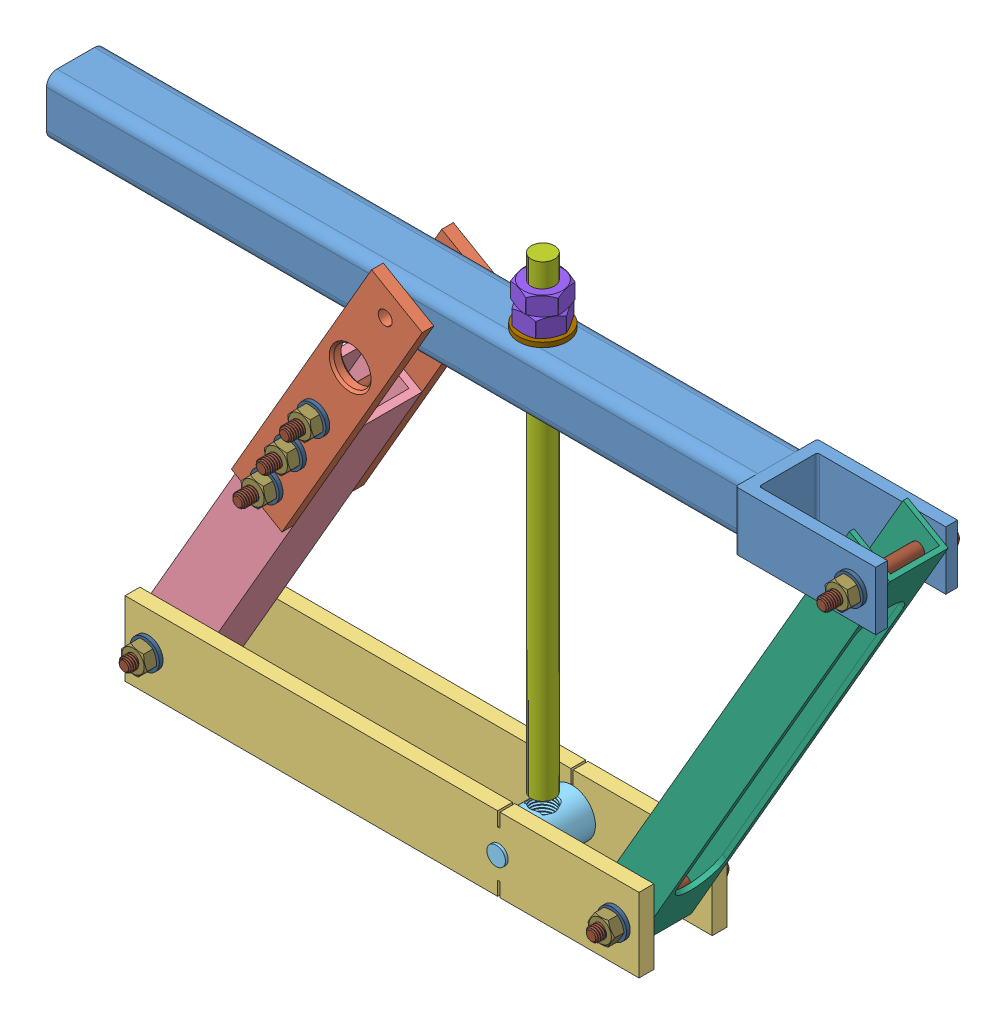
SolidWorks assembly ASSEMBLY, configuration Default. Lengths in mm.
Overall size (361.06 229.58 55.41).
36 component instances, 12 part files, 78 mates.
Components (placement in the parent):
- Base-1: Base [Default<As Machined>] at (-498.0765 -12.5 12.5) x (0 0 1) z (0 1 0) size (35 360 25)
- Base Arm-1: Base Arm [Default] at (-392.2512 -114.0128 0) x (-0.866025 0.5 0) z (0 0 -1) size (25 120 5)
- Beam-1: Beam [Default] at (-238.0765 -201.5801 0) x (-1 0 0) z (0 0 -1) size (220 31.75 6.35)
- Link-1: Link [Default] at (-362.2512 -62.0513 25) x (-0.866025 0.5 0) z (-0.5 -0.866025 0) size (25 25 160)
- nut-1: nut [Default] at (-313.4989 -170.565 32.5) x (0 0 -1) z (0 -1 0) size (40 20 25.35)
- strut-1: strut [Default] at (-290.91 81.512 250.1369) x (-0.866025 0.5 0) z (-0.5 -0.866025 0) size (20 25 220)
- tie-1: tie [Default] at (-298.0765 -172 12.5) x (-0.966291 0 0.257452) z (-0.257452 0 -0.966291) size (10 200 10)
- Beam-2: Beam [Default] at (-238.0765 -201.5801 31.35) x (-1 0 0) z (0 0 -1) size (220 31.75 6.35)
- Base Arm-2: Base Arm [Default] at (-392.2512 -114.0128 30) x (-0.866025 0.5 0) z (0 0 -1) size (25 120 5)
- M10-2: M10 [Default] at (-298.0765 6 12.5) x (-0.036581 0 -0.999331) z (0 -1 0) size (17 19.57 9.05)
- M10-3: M10 [Default] at (-298.0765 14 12.5) x (0.288728 0 -0.957411) z (0 -1 0) size (17 19.57 9.05)
- washer 10mm-1: washer 10mm [Default] at (-298.0765 2 12.5) x (-0.841207 0 -0.540714) z (0 -1 0) size (20.7 20.7 2)
- washer 6mm-1: washer 6mm [Default] at (-248.0765 -185.7051 32.95) x (-0.249725 -0.968317 0) z (0 0 -1) size (12.5 12.5 1.6)
- washer 6mm-2: washer 6mm [Default] at (-148.0765 -12.5 31.6) x (-0.286838 -0.957979 0) z (0 0 -1) size (12.5 12.5 1.6)
- washer 6mm-3: washer 6mm [Default] at (-448.0765 -185.7051 32.95) x (-0.286838 -0.957979 0) z (0 0 -1) size (12.5 12.5 1.6)
- washer 6mm-4: washer 6mm [Default] at (-388.0765 -81.782 31.6) x (-0.280456 -0.959867 0) z (0 0 -1) size (12.5 12.5 1.6)
- washer 6mm-5: washer 6mm [Default] at (-398.0765 -99.1025 31.6) x (-0.33668 -0.941619 0) z (0 0 -1) size (12.5 12.5 1.6)
- washer 6mm-6: washer 6mm [Default] at (-378.0765 -64.4615 31.6) x (-0.286026 -0.958222 0) z (0 0 -1) size (12.5 12.5 1.6)
- washer 6mm-7: washer 6mm [Default] at (-398.0765 -99.1025 -5) x (0.991493 -0.130162 0) z (0 0 -1) size (12.5 12.5 1.6)
- washer 6mm-8: washer 6mm [Default] at (-248.0765 -185.7051 -6.35) x (-0.263868 -0.964559 0) z (0 0 -1) size (12.5 12.5 1.6)
- washer 6mm-9: washer 6mm [Default] at (-448.0765 -185.7051 -6.35) x (-0.233498 -0.972357 0) z (0 0 -1) size (12.5 12.5 1.6)
- washer 6mm-10: washer 6mm [Default] at (-388.0765 -81.782 -5) x (-0.289092 -0.957301 0) z (0 0 -1) size (12.5 12.5 1.6)
- washer 6mm-11: washer 6mm [Default] at (-148.0765 -12.5 -5) x (-0.286838 -0.957979 0) z (0 0 -1) size (12.5 12.5 1.6)
- washer 6mm-12: washer 6mm [Default] at (-378.0765 -64.4615 -5) x (-0.274028 -0.961722 0) z (0 0 -1) size (12.5 12.5 1.6)
- m6 bolt-1: m6 bolt [Default] at (-148.0765 -12.5 -6.8) x (0.287505 0.957779 0) z (0 0 1) size (11.55 10 54.06)
- m6 nut-1: m6 nut [Default] at (-448.0765 -185.7051 32.95) x (0.693542 0.720416 0) z (0 0 1) size (11.55 10 5.69)
- m6 bolt-2: m6 bolt [Default] at (-378.0765 -64.4615 -6.8) x (0.287505 0.957779 0) z (0 0 1) size (11.55 10 54.06)
- m6 bolt-3: m6 bolt [Default] at (-398.0765 -99.1025 -6.8) x (0.287505 0.957779 0) z (0 0 1) size (11.55 10 54.06)
- m6 bolt-4: m6 bolt [Default] at (-388.0765 -81.782 -6.8) x (0.287505 0.957779 0) z (0 0 1) size (11.55 10 54.06)
- m6 bolt-5: m6 bolt [Default] at (-448.0765 -185.7051 -8.15) x (0.287505 0.957779 0) z (0 0 1) size (11.55 10 54.06)
- m6 bolt-6: m6 bolt [Default] at (-248.0765 -185.7051 -8.15) x (0.287505 0.957779 0) z (0 0 1) size (11.55 10 54.06)
- m6 nut-2: m6 nut [Default] at (-248.0765 -185.7051 32.95) x (-0.486561 0.873647 0) z (0 0 1) size (11.55 10 5.69)
- m6 nut-4: m6 nut [Default] at (-388.0765 -81.782 31.6) x (0.693542 0.720416 0) z (0 0 1) size (11.55 10 5.69)
- m6 nut-5: m6 nut [Default] at (-378.0765 -64.4615 31.6) x (0.693542 0.720416 0) z (0 0 1) size (11.55 10 5.69)
- m6 nut-6: m6 nut [Default] at (-398.0765 -99.1025 31.6) x (0.693542 0.720416 0) z (0 0 1) size (11.55 10 5.69)
- m6 nut-7: m6 nut [Default] at (-148.0765 -12.5 31.6) x (0.693542 0.720416 0) z (0 0 1) size (11.55 10 5.69)
Mates (geometry in assembly coordinates):
- Coincident1: coincident anti-aligned: plane of Base-1 through (-193.0765 0 25) normal (0 0 -1); plane of strut-1 through (-247.0143 -197.8653 25) normal (0 0 1)
- Concentric1: concentric aligned: circle of Base-1; circle of strut-1
- Coincident3: coincident anti-aligned: plane of Beam-1 through (-238.0765 -201.5801 0) normal (0 0 1); plane of strut-1 through (-247.0143 -197.8653 0) normal (0 0 -1)
- Concentric2: concentric aligned: circle of Beam-1; circle of strut-1
- Coincident5: coincident anti-aligned: plane of strut-1 through (-247.0143 -197.8653 25) normal (0 0 1); plane of Beam-2 through (-238.0765 -201.5801 25) normal (0 0 -1)
- Concentric3: concentric anti-aligned: cylinder of strut-1 through (-248.0765 -185.7051 220) axis (0 0 -1) radius 3; cylinder of Beam-2 through (-248.0765 -185.7051 25) axis (0 0 1) radius 3
- Concentric4: concentric aligned: cylinder of nut-1 through (-298.0765 -185.7051 25) axis (0 0 1) radius 4; cylinder of Beam-2 through (-298.0765 -185.7051 25) axis (0 0 1) radius 4
- Concentric5: concentric anti-aligned: cylinder of Beam-1 through (-298.0765 -185.7051 -6.35) axis (0 0 1) radius 4; cylinder of nut-1 through (-298.0765 -185.7051 0) axis (0 0 -1) radius 4
- Coincident6: coincident anti-aligned: plane of Beam-1 through (-238.0765 -201.5801 0) normal (0 0 1); plane of nut-1 through (-298.0765 -185.7051 0) normal (0 0 -1)
- Coincident7: coincident anti-aligned: plane of Beam-1 through (-238.0765 -201.5801 0) normal (0 0 1); plane of Link-1 through (-442.2512 -200.6153 0) normal (0 0 -1)
- Coincident8: coincident aligned: cylinder of Beam-1 through (-448.0765 -185.7051 -6.35) axis (0 0 1) radius 3; circle of Link-1
- Concentric6: concentric aligned: cylinder of Base Arm-1 through (-398.0765 -99.1025 -5) axis (0 0 1) radius 3; cylinder of Link-1 through (-398.0765 -99.1025 0) axis (0 0 1) radius 3
- Coincident9: coincident aligned: cylinder of Base Arm-1 through (-378.0765 -64.4615 -5) axis (0 0 1) radius 3; circle of Link-1
- Coincident10: coincident anti-aligned: plane of Base Arm-1 through (-392.2512 -114.0128 0) normal (0 0 1); plane of Link-1 through (-442.2512 -200.6153 0) normal (0 0 -1)
- Concentric7: concentric aligned: cylinder of Link-1 through (-378.0765 -64.4615 0) axis (0 0 1) radius 3; cylinder of Base Arm-2 through (-378.0765 -64.4615 25) axis (0 0 1) radius 3
- Coincident11: coincident anti-aligned: plane of Link-1 through (-442.2512 -200.6153 25) normal (0 0 1); plane of Base Arm-2 through (-392.2512 -114.0128 25) normal (0 0 -1)
- Concentric8: concentric anti-aligned: cylinder of Base-1 through (-298.0765 -3 12.5) axis (0 1 0) radius 5.25; cylinder of tie-1 through (-298.0765 28 12.5) axis (0 -1 0) radius 5
- Coincident13: coincident anti-aligned: cylinder of Link-1 through (-398.0765 -99.1025 0) axis (0 0 1) radius 3; circle of Base Arm-2
- Coincident14: coincident aligned: circle of nut-1; cylinder of tie-1 through (-298.0765 28 12.5) axis (0 -1 0) radius 5
- Concentric10: concentric aligned: circle of M10-2; circle of tie-1
- Angle1: planar angle = 1.047198 rad anti-aligned: line of Base-1 through (-138.0765 -25 -5) axis (-1 0 0); line of strut-1 through (-264.3348 -187.8653 0) axis (0.5 0.866025 0)
- Angle2: planar angle = 2.094395 rad aligned: line of Base Arm-2 through (-413.9018 -101.5128 25) axis (0.5 0.866025 0); line of Base-1 through (-138.0765 -25 -5) axis (-1 0 0)
- Concentric11: concentric anti-aligned: circle of tie-1; circle of M10-3
- Coincident15: coincident anti-aligned: plane of M10-2 through (-298.0765 10 12.5) normal (0 1 0); plane of M10-3 through (-298.0765 10 12.5) normal (0 -1 0)
- Concentric12: concentric anti-aligned: circle of Base-1; circle of 10mm washer-1
- Coincident17: coincident anti-aligned: plane of Base-1 through (-198.0765 0 20.5) normal (0 1 0); plane of washer 10mm-1 through (-298.0765 0 12.5) normal (0 -1 0)
- Coincident18: coincident anti-aligned: plane of M10-2 through (-298.0765 2 12.5) normal (0 -1 0); plane of washer 10mm-1 through (-298.0765 2 12.5) normal (0 1 0)
- Concentric14: concentric aligned: circle of Base-1; circle of 6mm washer-2
- Coincident20: coincident anti-aligned: plane of Base-1 through (-138.0765 -25 30) normal (0 0 1); plane of washer 6mm-2 through (-148.0765 -12.5 30) normal (0 0 -1)
- Concentric15: concentric aligned: circle of Beam-2; circle of 6mm washer-1
- Coincident21: coincident anti-aligned: plane of Beam-2 through (-238.0765 -201.5801 31.35) normal (0 0 1); plane of washer 6mm-1 through (-248.0765 -185.7051 31.35) normal (0 0 -1)
- Concentric16: concentric aligned: circle of Beam-2; circle of 6mm washer-3
- Coincident22: coincident anti-aligned: plane of Beam-2 through (-238.0765 -201.5801 31.35) normal (0 0 1); plane of washer 6mm-3 through (-448.0765 -185.7051 31.35) normal (0 0 -1)
- Concentric17: concentric aligned: circle of Base Arm-2; circle of 6mm washer-6
- Concentric18: concentric aligned: circle of Base Arm-2; circle of 6mm washer-4
- Concentric19: concentric aligned: circle of Base Arm-2; circle of 6mm washer-5
- Coincident23: coincident anti-aligned: plane of Base Arm-2 through (-392.2512 -114.0128 30) normal (0 0 1); plane of washer 6mm-5 through (-398.0765 -99.1025 30) normal (0 0 -1)
- Coincident24: coincident anti-aligned: plane of Base Arm-2 through (-392.2512 -114.0128 30) normal (0 0 1); plane of washer 6mm-4 through (-388.0765 -81.782 30) normal (0 0 -1)
- Coincident25: coincident anti-aligned: plane of Base Arm-2 through (-392.2512 -114.0128 30) normal (0 0 1); plane of washer 6mm-6 through (-378.0765 -64.4615 30) normal (0 0 -1)
- Concentric20: concentric aligned: circle of Beam-1; circle of 6mm washer-8
- Concentric21: concentric aligned: circle of Beam-1; circle of 6mm washer-9
- Concentric22: concentric aligned: circle of Base Arm-1; circle of 6mm washer-7
- Concentric23: concentric aligned: circle of Base Arm-1; circle of 6mm washer-10
- Concentric24: concentric aligned: circle of Base Arm-1; circle of 6mm washer-12
- Concentric25: concentric aligned: circle of Base-1; circle of 6mm washer-11
- Coincident26: coincident anti-aligned: plane of Beam-1 through (-238.0765 -201.5801 -6.35) normal (0 0 -1); plane of washer 6mm-9 through (-448.0765 -185.7051 -6.35) normal (0 0 1)
- Coincident27: coincident anti-aligned: plane of Beam-1 through (-238.0765 -201.5801 -6.35) normal (0 0 -1); plane of washer 6mm-8 through (-248.0765 -185.7051 -6.35) normal (0 0 1)
- Coincident28: coincident anti-aligned: plane of Base-1 through (-138.0765 -25 -5) normal (0 0 -1); plane of washer 6mm-11 through (-148.0765 -12.5 -5) normal (0 0 1)
- Coincident29: coincident anti-aligned: plane of Base Arm-1 through (-392.2512 -114.0128 -5) normal (0 0 -1); plane of washer 6mm-7 through (-398.0765 -99.1025 -5) normal (0 0 1)
- Coincident30: coincident anti-aligned: plane of Base Arm-1 through (-392.2512 -114.0128 -5) normal (0 0 -1); plane of washer 6mm-10 through (-388.0765 -81.782 -5) normal (0 0 1)
- Coincident31: coincident anti-aligned: plane of Base Arm-1 through (-392.2512 -114.0128 -5) normal (0 0 -1); plane of washer 6mm-12 through (-378.0765 -64.4615 -5) normal (0 0 1)
- Concentric26: concentric aligned: cylinder of Base-1 through (-148.0765 -12.5 50) axis (0 0 -1) radius 3; cylinder of m6 bolt-1 through (-148.0765 -12.5 43.2) axis (0 0 -1) radius 3
- Coincident32: coincident anti-aligned: plane of washer 6mm-11 through (-148.0765 -12.5 -6.6) normal (0 0 -1); plane of m6 bolt-1 through (-148.0765 -12.5 -6.6) normal (0 0 1)
- Coincident33: coincident anti-aligned: plane of washer 6mm-2 through (-148.0765 -12.5 31.6) normal (0 0 1); plane of m6 nut-7 through (-148.0765 -12.5 31.6) normal (0 0 -1)
- Concentric27: concentric anti-aligned: circle of washer 6mm-2; circle of m6 nut-7
- Concentric28: concentric anti-aligned: cylinder of Base Arm-1 through (-378.0765 -64.4615 -5) axis (0 0 1) radius 3; cylinder of m6 bolt-2 through (-378.0765 -64.4615 43.2) axis (0 0 -1) radius 3
- Concentric29: concentric anti-aligned: cylinder of Base Arm-1 through (-398.0765 -99.1025 -5) axis (0 0 1) radius 3; cylinder of m6 bolt-3 through (-398.0765 -99.1025 43.2) axis (0 0 -1) radius 3
- Concentric30: concentric anti-aligned: cylinder of Base Arm-1 through (-388.0765 -81.782 -5) axis (0 0 1) radius 3; cylinder of m6 bolt-4 through (-388.0765 -81.782 43.2) axis (0 0 -1) radius 3
- Concentric31: concentric anti-aligned: cylinder of Beam-1 through (-448.0765 -185.7051 -6.35) axis (0 0 1) radius 3; cylinder of m6 bolt-5 through (-448.0765 -185.7051 41.85) axis (0 0 -1) radius 3
- Concentric32: concentric anti-aligned: cylinder of Beam-1 through (-248.0765 -185.7051 -6.35) axis (0 0 1) radius 3; cylinder of m6 bolt-6 through (-248.0765 -185.7051 41.85) axis (0 0 -1) radius 3
- Coincident34: coincident anti-aligned: plane of washer 6mm-9 through (-448.0765 -185.7051 -7.95) normal (0 0 -1); plane of m6 bolt-5 through (-448.0765 -185.7051 -7.95) normal (0 0 1)
- Coincident36: coincident anti-aligned: plane of washer 6mm-12 through (-378.0765 -64.4615 -6.6) normal (0 0 -1); plane of m6 bolt-2 through (-378.0765 -64.4615 -6.6) normal (0 0 1)
- Coincident37: coincident anti-aligned: plane of washer 6mm-10 through (-388.0765 -81.782 -6.6) normal (0 0 -1); plane of m6 bolt-4 through (-388.0765 -81.782 -6.6) normal (0 0 1)
- Coincident38: coincident anti-aligned: plane of washer 6mm-7 through (-398.0765 -99.1025 -6.6) normal (0 0 -1); plane of m6 bolt-3 through (-398.0765 -99.1025 -6.6) normal (0 0 1)
- Coincident39: coincident anti-aligned: plane of washer 6mm-8 through (-248.0765 -185.7051 -7.95) normal (0 0 -1); plane of m6 bolt-6 through (-248.0765 -185.7051 -7.95) normal (0 0 1)
- Coincident40: coincident anti-aligned: plane of washer 6mm-1 through (-248.0765 -185.7051 32.95) normal (0 0 1); circle of m6 nut-2
- Concentric33: concentric anti-aligned: circle of washer 6mm-1; circle of m6 nut-2
- Coincident41: coincident anti-aligned: plane of washer 6mm-3 through (-448.0765 -185.7051 32.95) normal (0 0 1); plane of m6 nut-1 through (-448.0765 -185.7051 32.95) normal (0 0 -1)
- Concentric34: concentric anti-aligned: circle of washer 6mm-3; circle of m6 nut-1
- Coincident42: coincident anti-aligned: plane of washer 6mm-6 through (-378.0765 -64.4615 31.6) normal (0 0 1); plane of m6 nut-5 through (-378.0765 -64.4615 31.6) normal (0 0 -1)
- Coincident43: coincident anti-aligned: plane of washer 6mm-4 through (-388.0765 -81.782 31.6) normal (0 0 1); plane of m6 nut-4 through (-388.0765 -81.782 31.6) normal (0 0 -1)
- Coincident44: coincident anti-aligned: plane of washer 6mm-5 through (-398.0765 -99.1025 31.6) normal (0 0 1); plane of m6 nut-6 through (-398.0765 -99.1025 31.6) normal (0 0 -1)
- Concentric35: concentric anti-aligned: circle of washer 6mm-6; circle of m6 nut-5
- Concentric36: concentric anti-aligned: circle of washer 6mm-4; circle of m6 nut-4
- Concentric37: concentric anti-aligned: circle of washer 6mm-5; circle of m6 nut-6
- Distance2: distance = 10 mm aligned: plane of M10-3 through (-298.0765 18 12.5) normal (0 1 0); plane of tie-1 through (-298.0765 28 12.5) normal (0 1 0)
- Coincident51: coincident aligned: plane of Base-1 through (-198.0765 0 20.5) normal (0 1 0)
- Coincident52: coincident anti-aligned: plane of Base-1 through (-198.0765 -20.5 0) normal (0 0 -1)
